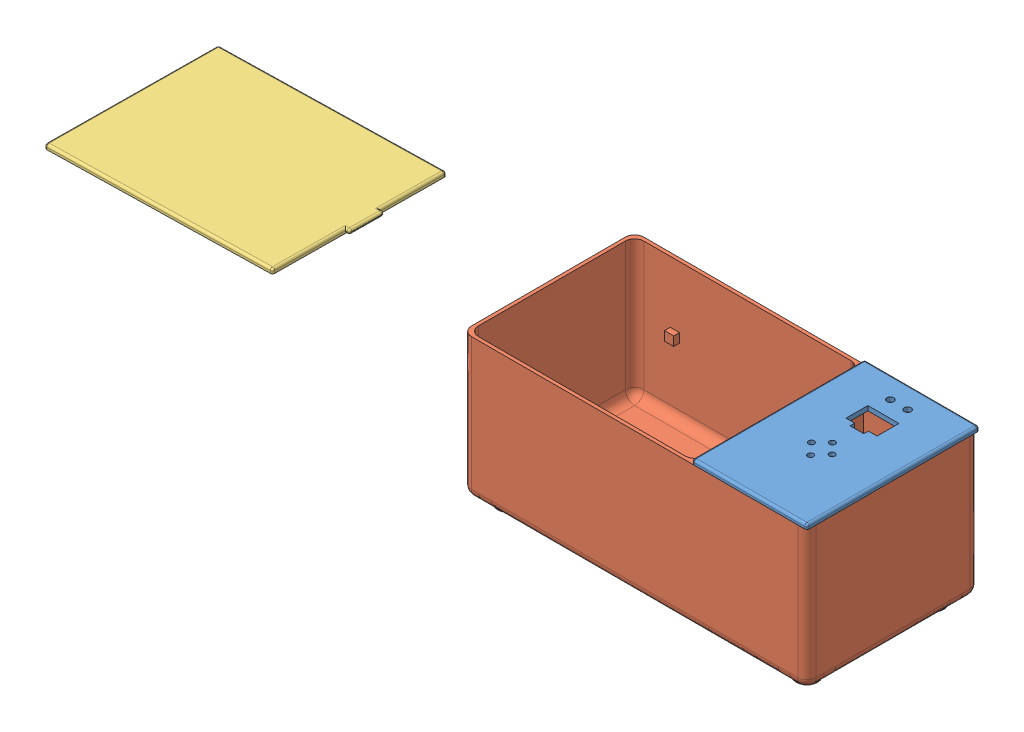
SolidWorks assembly Assem2, configuration Default. Lengths in mm.
Overall size (603.03 157.3 212.09).
3 component instances, 3 part files, 3 mates.
Components (placement in the parent):
- displaypart-1: displaypart [Default] at (-10.7264 74.4543 152.9416) size (100 4 150)
- enclosure-1: enclosure [Default] at (-210.7264 -48.5457 152.9416) size (300 131 150)
- top slider-1: top slider [Default] at (-306.8739 96.757 159.7701) x (0.999553 0.028794 0.008089) z (-0.008134 0.001445 0.999966) size (203.54 4 150)
Mates (geometry in assembly coordinates):
- Coincident1: coincident aligned: line of displaypart-1 through (-8.7264 74.4543 152.9416) axis (1 0 0); line of enclosure-1 through (-202.7264 74.4543 152.9416) axis (1 0 0)
- Parallel1: parallel aligned: line of displaypart-1 through (89.2736 74.4543 150.9416) axis (0 0 -1); line of enclosure-1 through (89.2736 74.4543 144.9416) axis (0 0 -1)
- Coincident5: coincident aligned: line of displaypart-1 through (89.2736 74.4543 150.9416) axis (0 0 -1); line of enclosure-1 through (89.2736 74.4543 144.9416) axis (0 0 -1)
